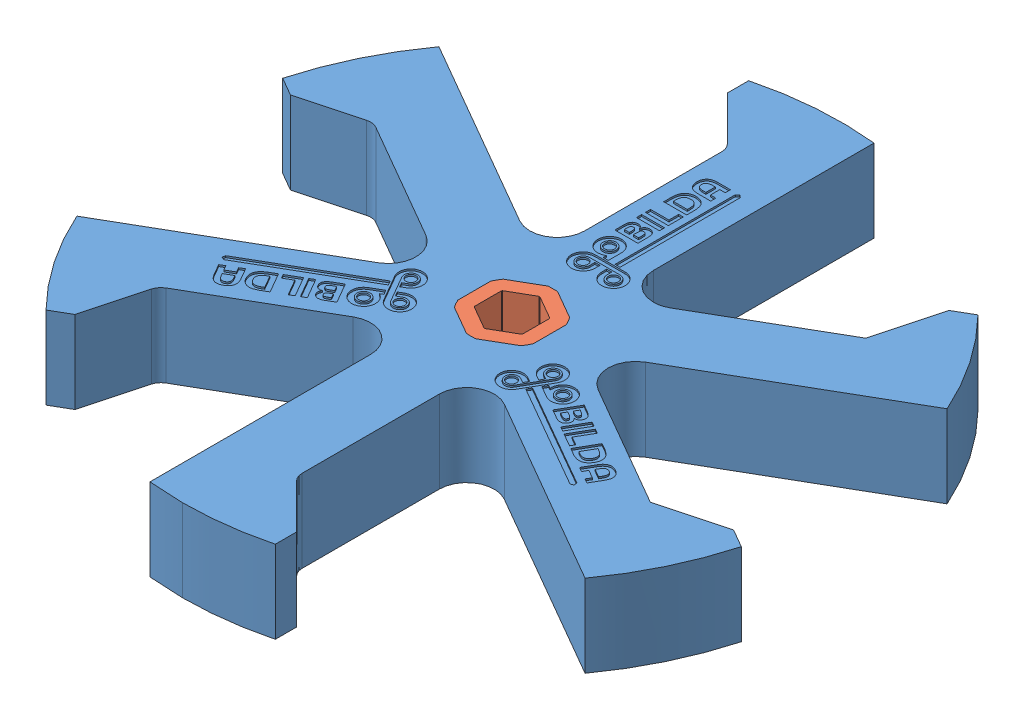
SolidWorks assembly 96mm Boot Wheel 3615-4008-0096, configuration Default. Lengths in mm.
Overall size (92.5 12 96).
2 component instances, 2 part files, 0 mates.
Components (placement in the parent):
- 3615-4008-0096 rubber.STEP-1: 3615-4008-0096 rubber.STEP [Default] at (-41.8185 11.2191 14.4449) size (92.5 12 96)
- 3615-4008-0096 Core.STEP-1: 3615-4008-0096 Core.STEP [Default] at (-41.8185 5.2191 14.4449) x (0.866025 0 0.5) z (-0.5 0 0.866025) size (12 12 11)
